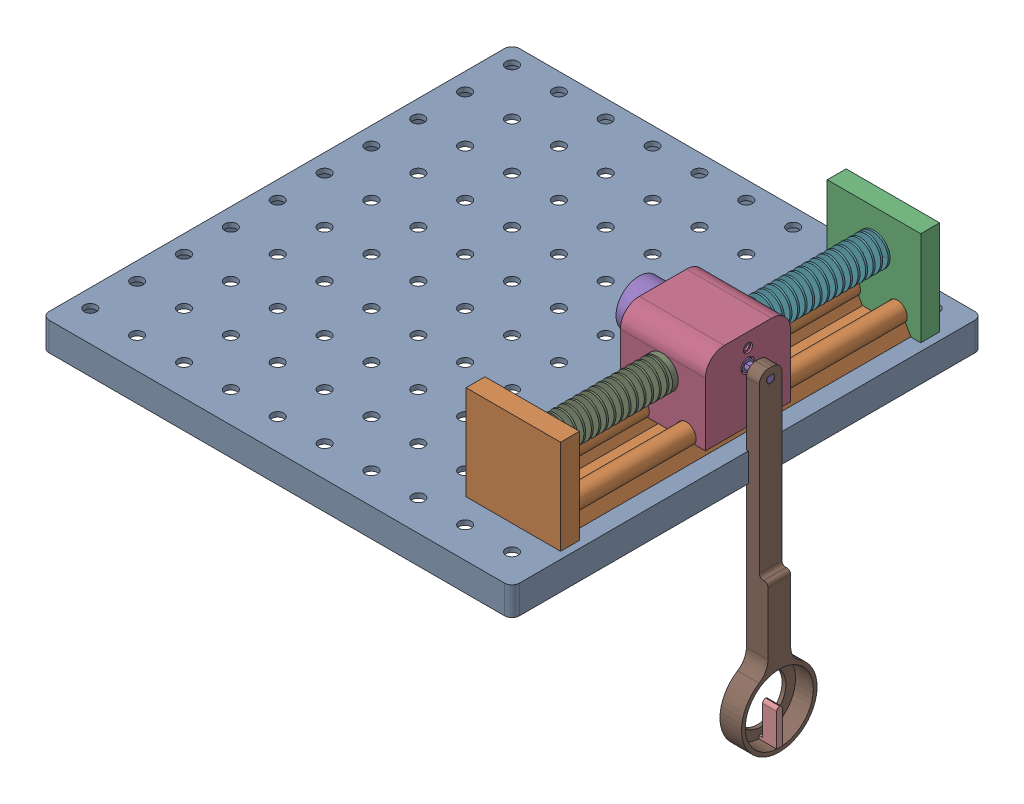
SolidWorks assembly #4 Assembly, configuration Default. Lengths in mm.
Overall size (259.41 185.82 249).
8 component instances, 7 part files, 13 mates.
Components (placement in the parent):
- pegboard-1: pegboard [Default] at (67.5473 79.5439 105.6076) x (1 0 0) z (0 0 -1) size (249 15 249)
- Linear_Rail_B-1: Linear_Rail_B [Default] at (136.3306 87.7401 4.2316) size (50 50 198.9)
- rail_2_wall-1: rail_2_wall [Default] at (150.6082 79.5439 22.5316) x (-1 0 0) z (0 0 -1) size (49.5 50 10)
- motor holder-1: motor holder [Default] at (140.494 112.6418 89.2613) size (45 43.33 45)
- motor 2 60RPM-2: motor 2 60RPM [Default] at (169.2306 112.6418 111.7613) x (0 0 1) z (-1 0 0) size (25 25 69.8)
- example spring xtheta-1: example spring xtheta [Default] at (148.7306 110.2401 23.4613) x (0 1 0) z (1 0 0) size (17.01 68.8 17)
- example spring xtheta-2: example spring xtheta [Default] at (148.7306 110.0439 137.6316) x (1 0 0) z (0 -1 0) size (17.01 68.8 17)
- pendulum xtheta motor-1: pendulum xtheta motor [Default] at (176.4306 51.224 111.7613) x (0 0 -1) z (1 0 0) size (40 174.08 11.41)
Mates (geometry in assembly coordinates):
- Coincident1: coincident anti-aligned: circle of pegboard-1; circle of Linear_Rail_B-1
- Concentric1: concentric anti-aligned: cylinder of Linear_Rail_B-1 through (161.1306 87.7401 224.2316) axis (0 0 -1) radius 5; cylinder of rail_2_wall-1 through (161.1306 87.7401 14.5316) axis (0 0 1) radius 5.2
- Concentric2: concentric anti-aligned: cylinder of Linear_Rail_B-1 through (136.3306 87.7401 224.2316) axis (0 0 -1) radius 5; cylinder of rail_2_wall-1 through (136.3306 87.7401 14.5316) axis (0 0 1) radius 5.2
- Coincident2: coincident anti-aligned: plane of Linear_Rail_B-1 through (136.3306 87.7401 14.5316) normal (0 0 -1); plane of rail_2_wall-1 through (161.1306 87.7401 14.5316) normal (0 0 1)
- Concentric3: concentric anti-aligned: cylinder of Linear_Rail_B-1 through (161.1306 87.7401 224.2316) axis (0 0 -1) radius 5; cylinder of motor holder-1 through (161.1306 87.7401 89.2613) axis (0 0 1) radius 5.2
- Concentric4: concentric anti-aligned: cylinder of Linear_Rail_B-1 through (136.3306 87.7401 224.2316) axis (0 0 -1) radius 5; cylinder of motor holder-1 through (136.3306 87.7401 89.2613) axis (0 0 1) radius 5.2
- Concentric5: concentric anti-aligned: cylinder of motor holder-1 through (172.2306 112.6418 111.7613) axis (-1 0 0) radius 12.7; cylinder of motor 2 60RPM-2 through (113.4306 112.6418 111.7613) axis (1 0 0) radius 12
- Coincident3: coincident anti-aligned: plane of motor holder-1 through (169.2306 112.6418 111.7613) normal (-1 0 0); plane of motor 2 60RPM-2 through (169.2306 112.6418 111.7613) normal (1 0 0)
- Coincident4: coincident anti-aligned: circle of motor holder-1; circle of example spring xtheta-1
- Concentric6: concentric anti-aligned: circle of Linear_Rail_B-1; circle of example spring xtheta-2
- Coincident5: coincident anti-aligned: plane of Linear_Rail_B-1 through (136.3306 87.7401 203.4316) normal (0 0 -1); plane of example spring xtheta-2 through (148.7306 110.0439 203.4316) normal (0 0 1)
- Concentric7: concentric anti-aligned: cylinder of motor 2 60RPM-2 through (183.2306 112.6418 111.7613) axis (-1 0 0) radius 2; cylinder of pendulum xtheta motor-1 through (176.4306 112.6418 111.7613) axis (1 0 0) radius 2.1774
- Coincident6: coincident aligned: plane of motor 2 60RPM-2 through (183.2306 112.6418 111.7613) normal (1 0 0); circle of pendulum xtheta motor-1
